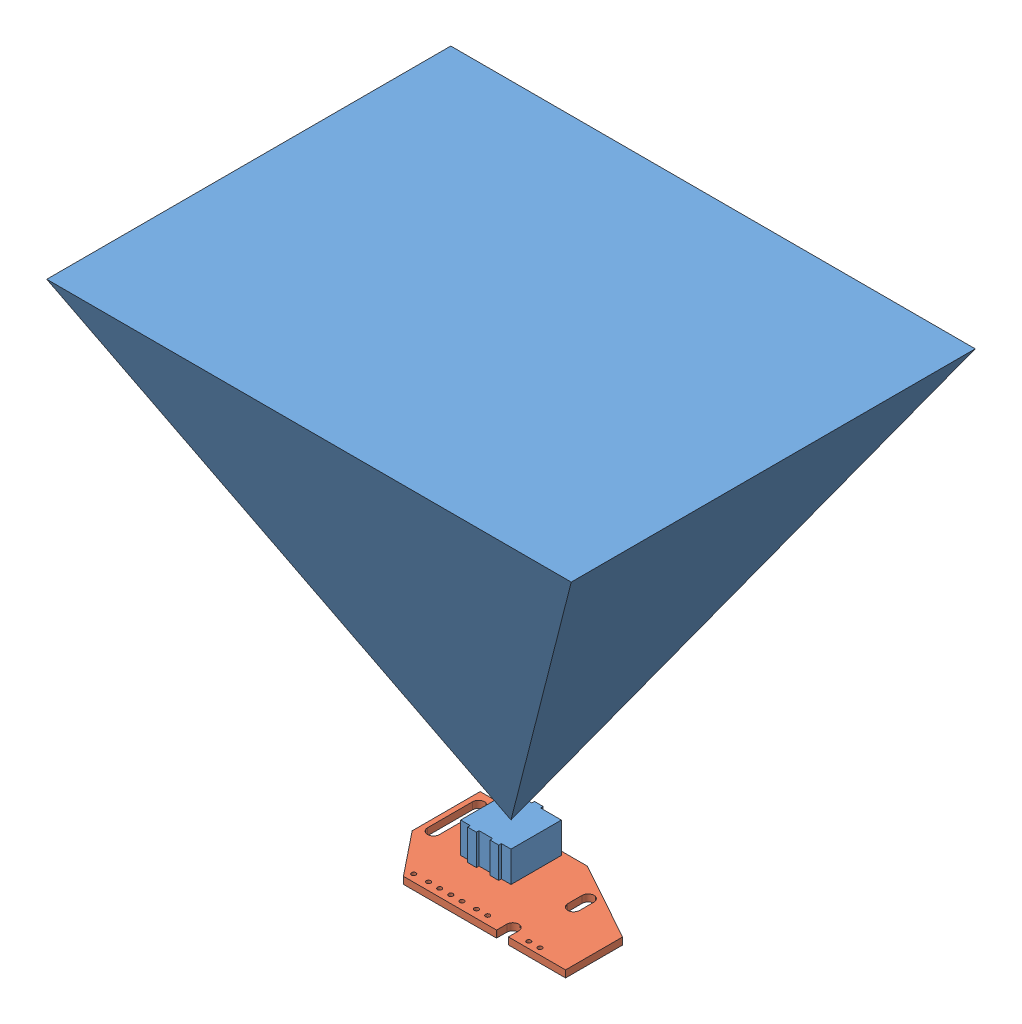
SolidWorks assembly Baugruppe1, configuration Standard. Lengths in mm.
Overall size (119.7 108.6 92.2).
2 component instances, 2 part files, 3 mates.
Components (placement in the parent):
- Flir-Kamera-mit-Sichtkegel-1: Flir-Kamera-mit-Sichtkegel [Standard] at (-15.4982 -22.988 119.6975) size (119.7 107 92.2)
- flir-board-1: flir-board [Standard] at (-9.1482 -22.988 123.3475) x (0 0 1) z (0 1 0) size (25.5 45 1.6)
Mates (geometry in assembly coordinates):
- Deckungsgleich1: coincident: plane of Flir-Kamera-mit-Sichtkegel-1 through (-15.4982 -22.988 119.6975) normal (0 -1 0); plane of flir-board-1 through (-10.8417 -22.988 124.5713) normal (0 1 0)
- Abstand1: distance = 0.25 mm: plane of flir-board-1 through (-4.6482 -22.988 113.0975) normal (0 0 -1); plane of Flir-Kamera-mit-Sichtkegel-1 through (-16.4982 -15.988 113.3475) normal (0 0 -1)
- Abstand2: distance = 5.1 mm: plane of Flir-Kamera-mit-Sichtkegel-1 through (-9.7482 -15.988 125.4475) normal (1 0 0); line of flir-board-1 through (-4.6482 -22.988 113.0975) axis (0 -1 0)
